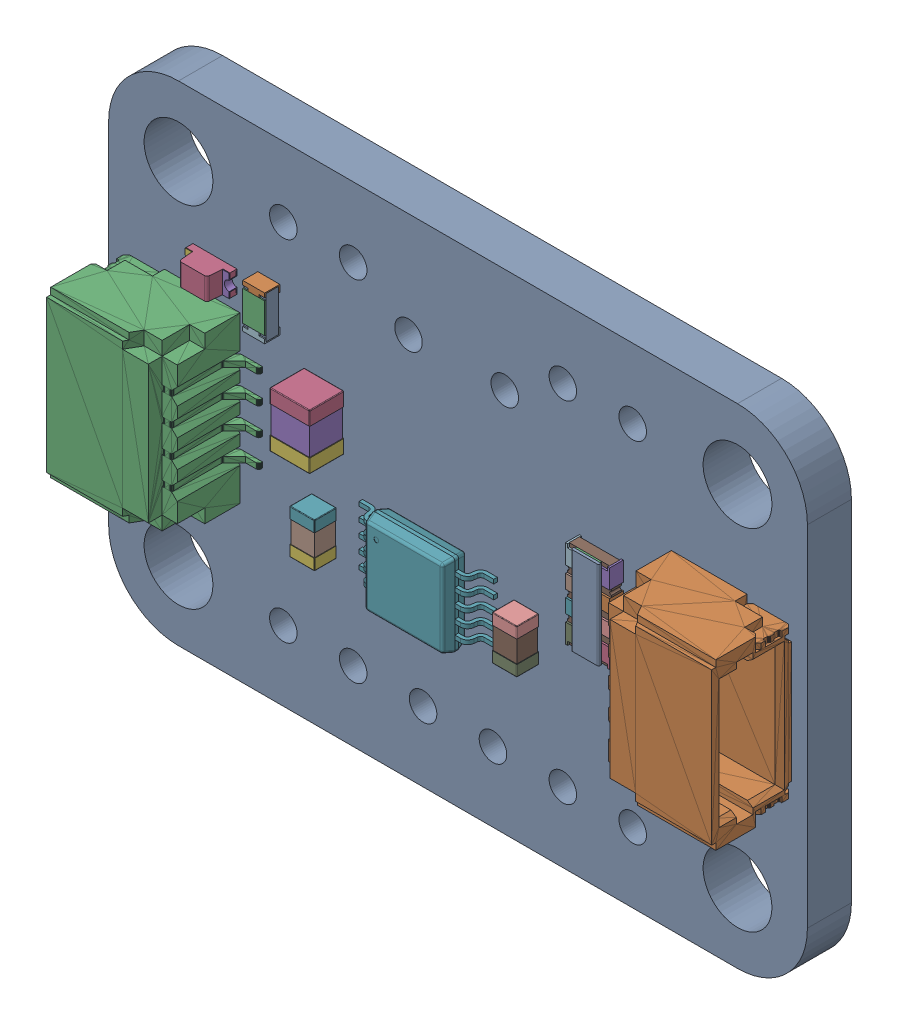
SolidWorks assembly AD5693R_Breakout_Assembly, configuration Default. Lengths in mm.
Overall size (25.4 17.78 4.5).
10 component instances, 8 part files, 20 mates.
Components (placement in the parent):
- AD5693R_Board_Base-1: AD5693R_Board_Base [Default] at origin size (25.4 17.78 1.6)
- STEMMA QT Horizontal-1: STEMMA QT Horizontal [Default] at (20.924 9.0704 -0.355) x (0 1 0) z (1 0 0) size (6 2.96 4.95)
- STEMMA QT Horizontal-2: STEMMA QT Horizontal [Default] at (4.5395 8.7151 -0.355) x (0 -1 0) z (-1 0 0) size (6 2.96 4.95)
- CC0805ZKY5V6BB106-1: CC0805ZKY5V6BB106 [Default] at (8.5556 10.034 0.625) x (0 -1 0) z (0 0 -1) size (2 1.45 1.25)
- CAY16-1821F4LF-1: CAY16-1821F4LF [Default] at (17.9088 9.181 0) x (-1 -0.000437 0) z (-0.000437 1 0) size (1.6 0.6 3.2)
- CC0603KRX7R7BB104-1: CC0603KRX7R7BB104 [Default] at (8.2806 6.417 0.4) x (0 1 0) z (0 0 1) size (1.6 0.9 0.8)
- CC0603KRX7R7BB104-2: CC0603KRX7R7BB104 [Default] at (14.7367 6.7537 0.4) x (0 1 0) z (0 0 -1) size (1.6 0.9 0.8)
- RC0603FR-0710KL-1: RC0603FR-0710KL [Default] at (5.823 12.4185 0) x (0 1 0) z (1 0 0) size (1.6 0.55 0.8)
- LTST-C190GKT-1: LTST-C190GKT [Default] at (3.8636 12.5238 0) x (1 0 0) z (0 -1 0) size (1.6 0.8 0.8)
- AD5693RARMZ-RL7-1: AD5693RARMZ-RL7 [Default] at (11.6786 6.8756 0.525) x (0 1 0) z (-1 0 0) size (3 0.95 4.9)
Mates (geometry in assembly coordinates):
- Coincident19: coincident anti-aligned: plane of AD5693R_Board_Base-1 through (22.86 15.24 0) normal (0 0 1); plane of STEMMA QT Horizontal-2 through (4.5395 8.7151 0) normal (0 0 -1)
- Coincident21: coincident anti-aligned: line of AD5693R_Board_Base-1 through (0.6445 5.79 0) axis (0 1 0); line of STEMMA QT Horizontal-2 through (0.6445 10.9151 0) axis (0 -1 0)
- Coincident22: coincident anti-aligned: plane of AD5693R_Board_Base-1 through (22.86 15.24 0) normal (0 0 1); plane of STEMMA QT Horizontal-1 through (20.924 9.0704 0) normal (0 0 -1)
- Coincident23: coincident anti-aligned: line of AD5693R_Board_Base-1 through (24.819 11.99 0) axis (0 -1 0); line of STEMMA QT Horizontal-1 through (24.819 6.8704 0) axis (0 1 0)
- Coincident24: coincident anti-aligned: line of AD5693R_Board_Base-1 through (17.0435 10.871 0) axis (1 0 0); line of CAY16-1821F4LF.step-1 through (18.4972 10.871 0) axis (-1 0 0)
- Parallel7: parallel anti-aligned: line of AD5693R_Board_Base-1 through (7.3025 10.033 0) axis (1 0 0); line of CC0805ZKY5V6BB106-1 through (8.5306 11.034 0.025) axis (-1 0 0)
- Coincident26: coincident anti-aligned: plane of AD5693R_Board_Base-1 through (22.86 15.24 0) normal (0 0 1); plane of CC0805ZKY5V6BB106-1 through (7.1056 11.034 0) normal (0 0 -1)
- Coincident27: coincident anti-aligned: line of AD5693R_Board_Base-1 through (13.084 5.458 0) axis (-1 0 0); line of AD5693RARMZ-RL7-1 through (10.2185 5.458 0) axis (1 0 0)
- Parallel8: parallel anti-aligned: line of AD5693R_Board_Base-1 through (7.1505 9.652 0) axis (0 1 0); line of CC0805ZKY5V6BB106-1 through (7.1056 11.009 0.025) axis (0 -1 0)
- Coincident28: coincident anti-aligned: plane of AD5693R_Board_Base-1 through (22.86 15.24 0) normal (0 0 1); plane of CAY16-1821F4LF-1 through (17.9088 9.181 0) normal (0 0 -1)
- Coincident31: coincident anti-aligned: plane of AD5693R_Board_Base-1 through (22.86 15.24 0) normal (0 0 1); plane of CC0603KRX7R7BB104-1 through (7.3806 7.217 0) normal (0 0 -1)
- Coincident32: coincident anti-aligned: plane of AD5693R_Board_Base-1 through (22.86 15.24 0) normal (0 0 1); plane of CC0603KRX7R7BB104-2 through (15.6367 5.9537 0) normal (0 0 -1)
- Parallel11: parallel aligned: line of AD5693R_Board_Base-1 through (15.6085 7.087 0) axis (0 -1 0); line of CC0603KRX7R7BB104-2 through (15.6367 7.5337 0.02) axis (0 -1 0)
- Parallel12: parallel aligned: line of AD5693R_Board_Base-1 through (8.2425 6.7695 0) axis (0 -1 0); line of CC0603KRX7R7BB104-1 through (8.2806 7.197 0.02) axis (0 -1 0)
- Coincident36: coincident anti-aligned: plane of AD5693R_Board_Base-1 through (22.86 15.24 0) normal (0 0 1); plane of RC0201FR-0710KL-1 through (3.8776 12.5385 0) normal (0 0 -1)
- Coincident37: coincident anti-aligned: plane of AD5693R_Board_Base-1 through (22.86 15.24 0) normal (0 0 1); plane of RC0603FR-0710KL-1 through (5.823 12.4185 0) normal (0 0 -1)
- Coincident38: coincident: line of AD5693R_Board_Base-1 through (5.423 12.802 0) axis (0 -1 0); plane of RC0603FR-0710KL-1 through (5.423 11.6185 0.55) normal (-1 0 0)
- Coincident40: coincident anti-aligned: plane of AD5693R_Board_Base-1 through (22.86 15.24 0) normal (0 0 1); plane of LTST-C190GKT-1 through (4.6636 12.1238 0) normal (0 0 -1)
- Coincident41: coincident anti-aligned: plane of AD5693R_Board_Base-1 through (22.86 15.24 0) normal (0 0 1); plane of AD5693RARMZ-RL7-1 through (9.5767 7.9506 0) normal (0 0 -1)
- Parallel13: parallel aligned: line of AD5693R_Board_Base-1 through (13.084 5.458 0) axis (-1 0 0); line of AD5693RARMZ-RL7-1 through (13.0786 5.3756 0.59) axis (-1 0 0)
